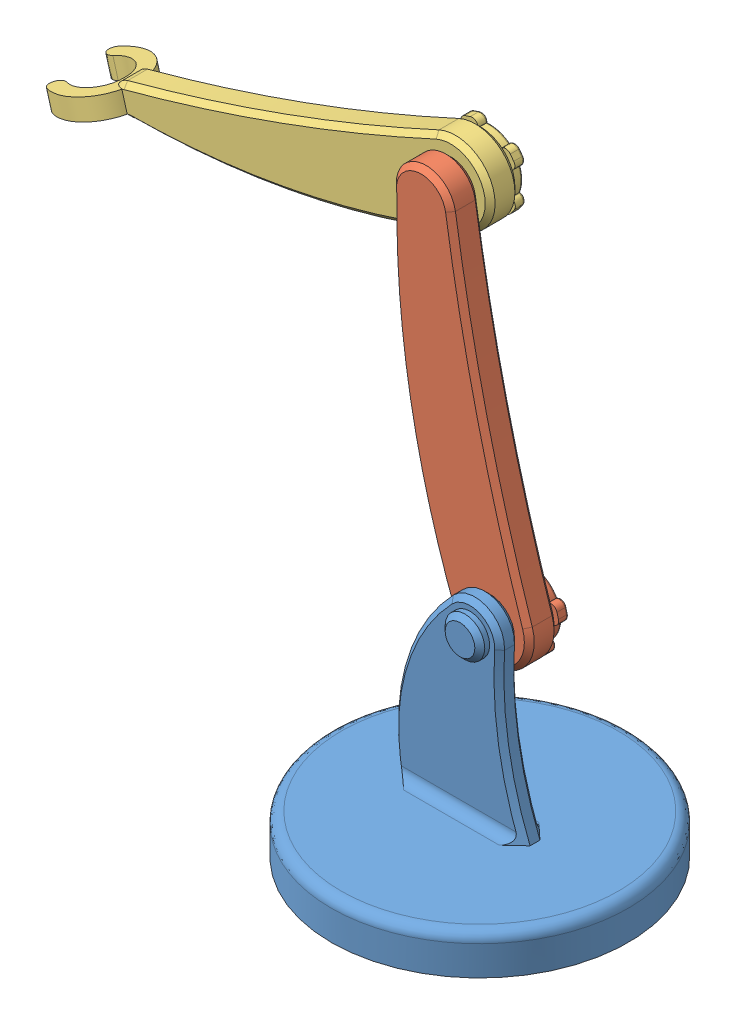
SolidWorks assembly Arm, configuration Default. Lengths in mm.
Overall size (308.95 291.76 150).
3 component instances, 3 part files, 5 mates.
Components (placement in the parent):
- Link_0-1: Link_0 [Default] at (21.8113 0 153.9507) size (150 115 150)
- Link_1-1: Link_1 [Default] at (4.4887 183.2162 141.4507) x (-0.203795 0.979014 0) z (0 0 -1) size (205 46.01 30.09)
- Link_2-1: Link_2 [Default] at (-94.7743 243.9846 126.4507) x (-0.962529 -0.271178 0) z (0 0 -1) size (221.29 43.24 41.34)
Mates (geometry in assembly coordinates):
- Coincident1: coincident aligned: plane of Link_0-1 through (21.8113 0 153.9507) normal (0 1 0)
- Coincident2: coincident anti-aligned: plane of Link_0-1 through (83.2901 41.3028 148.9507) normal (0 0 -1); plane of Link_1-1 through (4.4887 183.2162 148.9507) normal (0 0 1)
- Concentric1: concentric aligned: cylinder of Link_0-1 through (21.8113 100 158.9507) axis (0 0 -1) radius 5; cylinder of Link_1-1 through (21.8113 100 158.9507) axis (0 0 -1) radius 5
- Coincident3: coincident anti-aligned: plane of Link_1-1 through (4.4887 183.2162 133.9507) normal (0 0 -1); plane of Link_2-1 through (-94.7743 243.9846 133.9507) normal (0 0 1)
- Concentric2: concentric aligned: cylinder of Link_1-1 through (-12.9593 267.0347 143.9507) axis (0 0 -1) radius 5; cylinder of Link_2-1 through (-12.9593 267.0347 143.9507) axis (0 0 -1) radius 5
